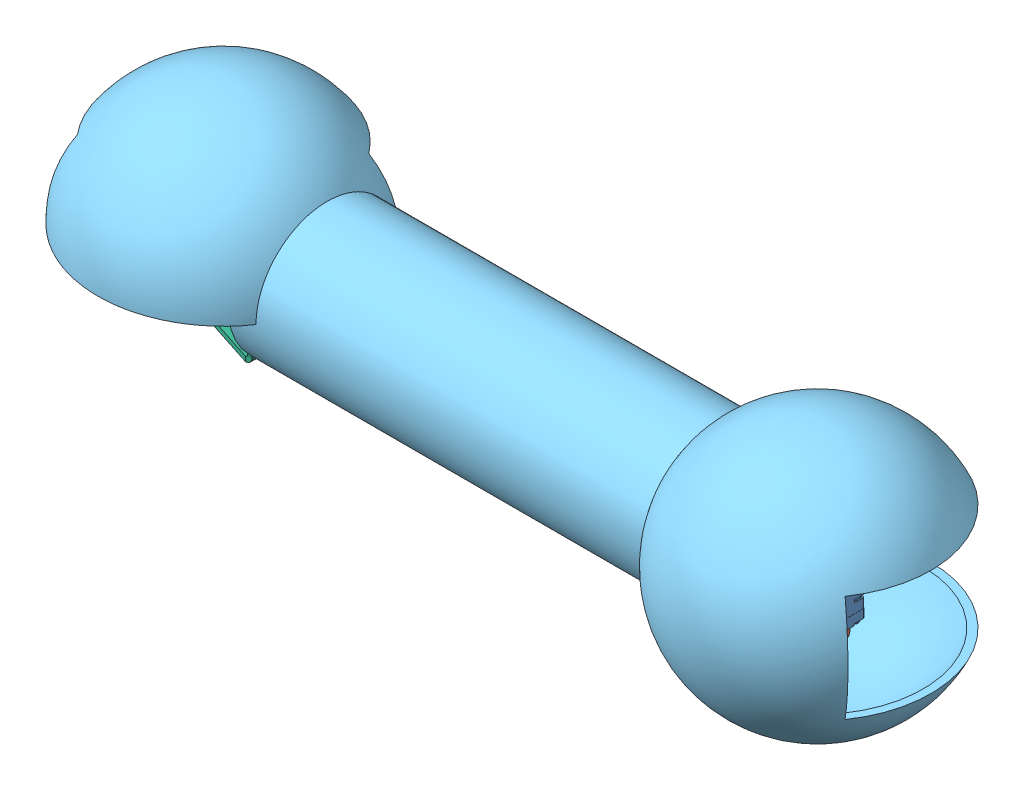
SolidWorks assembly upper, configuration 默认. Lengths in mm.
Overall size (342.08 106 100.99).
7 component instances, 6 part files, 9 mates.
Components (placement in the parent):
- 舵机-1: 舵机 [默认] at origin size (43.48 52.6 27.66)
  - 舵机-1: 舵机 [默认] at origin size (40 51.4 20)
  - 副舵盘-1: 副舵盘 [默认] at (9.65 -0.8 0) x (-0.933258 0 -0.359207) z (-0.359207 0 0.933258) size (20 5 20)
  - 主舵盘-1: 主舵盘 [默认] at (9.65 40.8 0) x (0.838844 0 0.544372) z (-0.544372 0 0.838844) size (20 5 20)
- 短U支架-1: 短U支架 [默认] at (-28 20 0) x (0 1 0) z (0 0 -1) size (44 22 40)
- 23号舵机连接管-1: 23号舵机连接管 [默认] at (-30 20 0) x (0 1 0) z (0 0 1) size (106 342.08 100.99)
- 大U支架-1: 大U支架 [默认] at (-210.35 20 0) x (0 1 0) z (0 0 1) size (51.6 42 40)
Mates (geometry in assembly coordinates):
- 重合1: coincident anti-aligned: plane of 舵机-1/舵机-1 through (0 40 0) normal (0 1 0); plane of 短U支架-1 through (-28 40 0) normal (0 -1 0)
- 同心1: concentric anti-aligned: circle of 舵机-1/舵机-1; circle of 短U支架-1
- 同心2: concentric anti-aligned: circle of 舵机-1/舵机-1; circle of 短U支架-1
- 重合2: coincident anti-aligned: plane of 短U支架-1 through (-30 20 0) normal (-1 0 0); plane of 23号舵机连接管-1 through (-30 20 0) normal (1 0 0)
- 重合3: coincident aligned: circle of 短U支架-1; circle of 23号舵机连接管-1
- 重合4: coincident aligned: circle of 短U支架-1; circle of 23号舵机连接管-1
- 重合5: coincident anti-aligned: plane of 23号舵机连接管-1 through (-208.35 20 0) normal (-1 0 0); plane of 大U支架-1 through (-208.35 20 0) normal (1 0 0)
- 同心3: concentric anti-aligned: circle of 23号舵机连接管-1; circle of 大U支架-1
- 同心4: concentric anti-aligned: circle of 23号舵机连接管-1; circle of 大U支架-1
